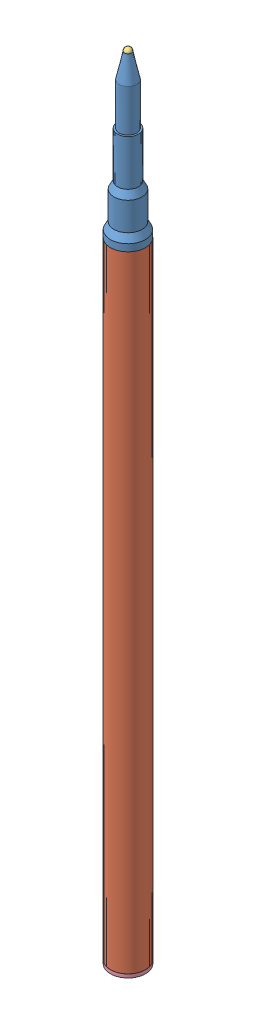
SolidWorks assembly Pen inkwell assembly, configuration Default. Lengths in mm.
Overall size (6.31 113.28 6.31).
4 component instances, 4 part files, 5 mates.
Components (placement in the parent):
- Pen ink tip-1: Pen ink tip [Default] at (25.6673 5.0658 19.9488) size (5 28 5)
- Pen inkwell-1: Pen inkwell [Default] at (25.6673 -78.9342 19.9488) size (5 89 5)
- pen roller ball-1: pen roller ball [Default] at (25.6673 33.0658 19.9488) x (0.127408 -0.669313 0.731975) z (-0.328988 -0.724728 -0.605422) size (1 1 1)
- pen inkwell cap-1: pen inkwell cap [Default] at (25.6673 -75.9342 19.9488) x (-0.950016 0 -0.312203) z (-0.312203 0 0.950016) size (5 3.5 5)
Mates (geometry in assembly coordinates):
- Concentric1: concentric aligned: cylinder of Pen ink tip-1 through (25.6673 10.0658 19.9488) axis (0 -1 0) radius 2.25; cylinder of Pen inkwell-1 through (25.6673 10.0658 19.9488) axis (0 -1 0) radius 2.25
- Coincident1: coincident anti-aligned: plane of Pen ink tip-1 through (25.6673 10.0658 19.9488) normal (0 -1 0); plane of Pen inkwell-1 through (25.6673 10.0658 19.9488) normal (0 1 0)
- Coincident2: coincident: circle of Pen ink tip-1; sphere of pen roller ball-1
- Concentric2: concentric anti-aligned: cylinder of Pen inkwell-1 through (25.6673 10.0658 19.9488) axis (0 -1 0) radius 2.25; cylinder of pen inkwell cap-1 through (25.6673 -78.9342 19.9488) axis (0 1 0) radius 2.25
- Coincident3: coincident anti-aligned: plane of Pen inkwell-1 through (25.6673 -78.9342 19.9488) normal (0 -1 0); plane of pen inkwell cap-1 through (25.6673 -78.9342 19.9488) normal (0 1 0)
